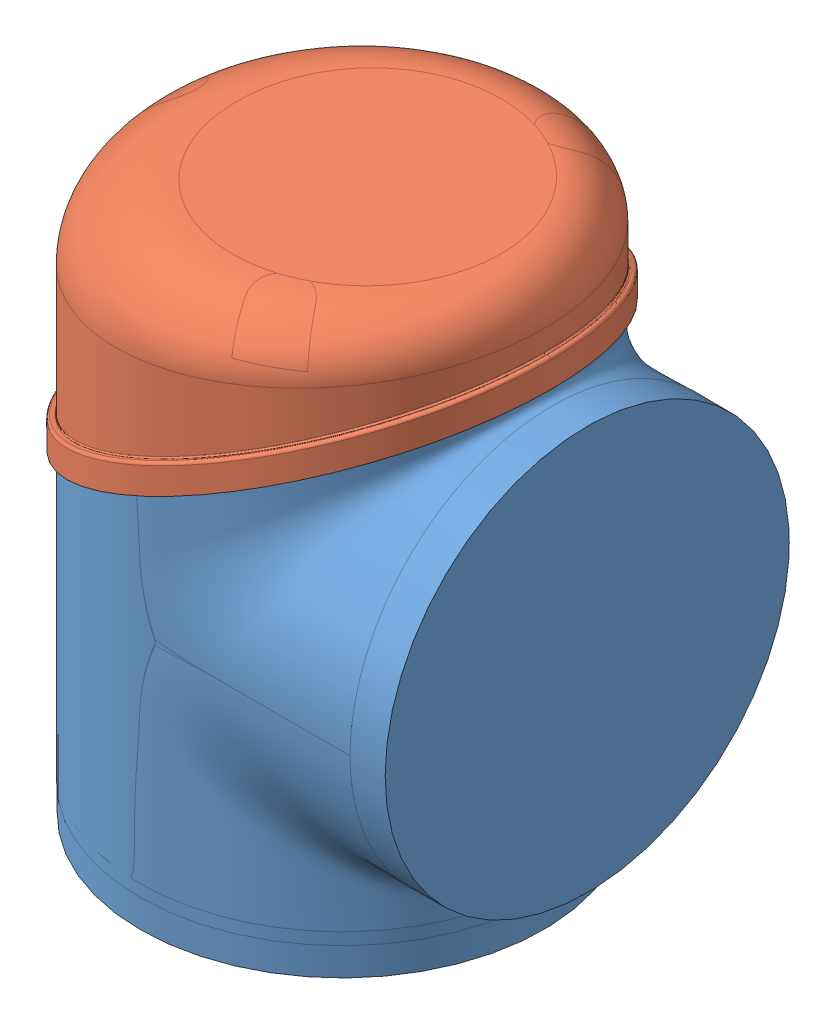
SolidWorks assembly House small, configuration Default. Lengths in mm.
Overall size (84.25 104.71 77.52).
2 component instances, 2 part files, 2 mates.
Components (placement in the parent):
- Size 1_House_r13_Simple-1: Size 1_House_r13_Simple [Default] at (-34.0745 6.3813 14.0822) size (83 87.5 75.48)
- Size 1_Joint lid_r07_Simple-1: Size 1_Joint lid_r07_Simple [Default] at (-34.0745 6.3813 14.0822) size (77.5 51.3 77.52)
Mates (geometry in assembly coordinates):
- Coincident1: coincident anti-aligned: plane of Size 1_House_r13_Simple-1 through (-42.536 25.612 14.0822) normal (-0.402739 0.915315 0); plane of Size 1_Joint lid_r07_Simple-1 through (7.9638 47.8319 168.7706) normal (0.402739 -0.915315 0)
- Concentric1: concentric aligned: cylinder of Size 1_House_r13_Simple-1 through (-34.0745 -46.6517 14.0822) axis (0 1 0) radius 37.5; cylinder of Size 1_Joint lid_r07_Simple-1 through (-34.0745 11.7978 14.0822) axis (0 1 0) radius 38.75
